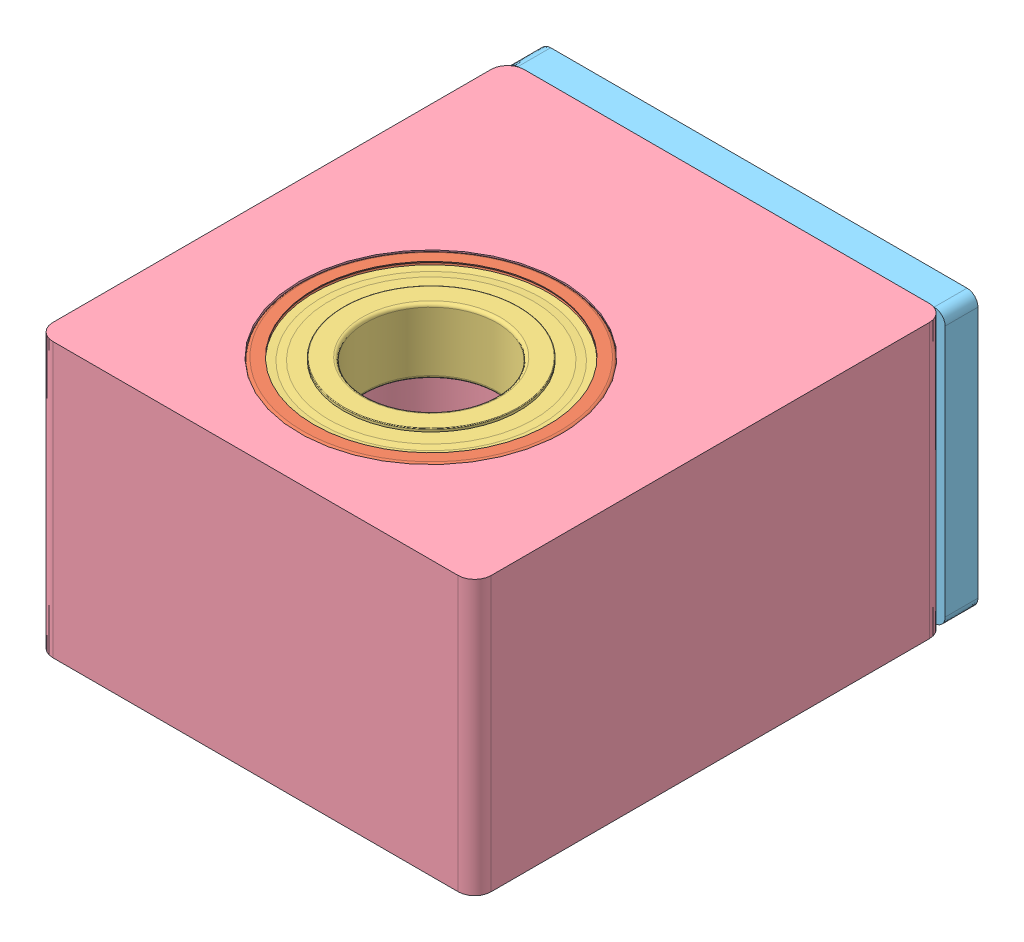
SolidWorks assembly Bearing House v1.step, configuration Default. Lengths in mm.
Overall size (40 25 45.94).
28 component instances, 5 part files, 0 mates.
Components (placement in the parent):
- SKF_61901-2Z.step-1: SKF_61901-2Z.step [Default] at (0 -8 19.5) x (0 -1 0) z (0 0 1) size (6 24 24)
  - SKF_61901-2Z_ball1.step-1: SKF_61901-2Z_ball1.step [Default] at (6 16.2812 -5.2901) x (-1 0 0) z (0 0 1) size (3.18 3.17 3.17)
  - SKF_61901-2Z_ball1.step-2: SKF_61901-2Z_ball1.step [Default] at (6 11.7812 -8.5595) x (-1 0 0) z (0 0 1) size (3.18 3.17 3.17)
  - SKF_61901-2Z_ball1.step-3: SKF_61901-2Z_ball1.step [Default] at (6 6.2188 -8.5595) x (-1 0 0) z (0 0 1) size (3.18 3.17 3.17)
  - SKF_61901-2Z_ball1.step-4: SKF_61901-2Z_ball1.step [Default] at (6 1.7188 -5.2901) x (-1 0 0) z (0 0 1) size (3.18 3.17 3.17)
  - SKF_61901-2Z_ball1.step-5: SKF_61901-2Z_ball1.step [Default] at (6 0 0) x (-1 0 0) z (0 0 1) size (3.18 3.17 3.17)
  - SKF_61901-2Z_ball1.step-6: SKF_61901-2Z_ball1.step [Default] at (6 1.7188 5.2901) x (-1 0 0) z (0 0 1) size (3.18 3.17 3.17)
  - SKF_61901-2Z_ball1.step-7: SKF_61901-2Z_ball1.step [Default] at (6 6.2188 8.5595) x (-1 0 0) z (0 0 1) size (3.18 3.17 3.17)
  - SKF_61901-2Z_ball1.step-8: SKF_61901-2Z_ball1.step [Default] at (6 11.7812 8.5595) x (-1 0 0) z (0 0 1) size (3.18 3.17 3.17)
  - SKF_61901-2Z_ball1.step-9: SKF_61901-2Z_ball1.step [Default] at (6 16.2812 5.2901) x (-1 0 0) z (0 0 1) size (3.18 3.17 3.17)
  - SKF_61901-2Z_ball1.step-10: SKF_61901-2Z_ball1.step [Default] at (6 18 0) x (-1 0 0) z (0 0 1) size (3.18 3.17 3.17)
  - SKF_61901-2Z_or.step-1: SKF_61901-2Z_or.step [Default] x (1 0 0) z (0 0 -1) size (6 24 24)
  - SKF_61901-2Z_ir.step-1: SKF_61901-2Z_ir.step [Default] x (1 0 0) z (0 0 -1) size (6 21.4 21.4)
- SKF_61901-2Z.step-2: SKF_61901-2Z.step [Default] at (0 5 19.5) x (0 1 0) z (0 0 1) size (6 24 24)
  - SKF_61901-2Z_ball1.step-1: SKF_61901-2Z_ball1.step [Default] at (6 16.2812 -5.2901) x (-1 0 0) z (0 0 1) size (3.18 3.17 3.17)
  - SKF_61901-2Z_ball1.step-2: SKF_61901-2Z_ball1.step [Default] at (6 11.7812 -8.5595) x (-1 0 0) z (0 0 1) size (3.18 3.17 3.17)
  - SKF_61901-2Z_ball1.step-3: SKF_61901-2Z_ball1.step [Default] at (6 6.2188 -8.5595) x (-1 0 0) z (0 0 1) size (3.18 3.17 3.17)
  - SKF_61901-2Z_ball1.step-4: SKF_61901-2Z_ball1.step [Default] at (6 1.7188 -5.2901) x (-1 0 0) z (0 0 1) size (3.18 3.17 3.17)
  - SKF_61901-2Z_ball1.step-5: SKF_61901-2Z_ball1.step [Default] at (6 0 0) x (-1 0 0) z (0 0 1) size (3.18 3.17 3.17)
  - SKF_61901-2Z_ball1.step-6: SKF_61901-2Z_ball1.step [Default] at (6 1.7188 5.2901) x (-1 0 0) z (0 0 1) size (3.18 3.17 3.17)
  - SKF_61901-2Z_ball1.step-7: SKF_61901-2Z_ball1.step [Default] at (6 6.2188 8.5595) x (-1 0 0) z (0 0 1) size (3.18 3.17 3.17)
  - SKF_61901-2Z_ball1.step-8: SKF_61901-2Z_ball1.step [Default] at (6 11.7812 8.5595) x (-1 0 0) z (0 0 1) size (3.18 3.17 3.17)
  - SKF_61901-2Z_ball1.step-9: SKF_61901-2Z_ball1.step [Default] at (6 16.2812 5.2901) x (-1 0 0) z (0 0 1) size (3.18 3.17 3.17)
  - SKF_61901-2Z_ball1.step-10: SKF_61901-2Z_ball1.step [Default] at (6 18 0) x (-1 0 0) z (0 0 1) size (3.18 3.17 3.17)
  - SKF_61901-2Z_or.step-1: SKF_61901-2Z_or.step [Default] x (1 0 0) z (0 0 -1) size (6 24 24)
  - SKF_61901-2Z_ir.step-1: SKF_61901-2Z_ir.step [Default] x (1 0 0) z (0 0 -1) size (6 21.4 21.4)
- Universal Bearing Housing.step-1: Universal Bearing Housing.step [Default] at (0 11.0044 14.0358) x (1 0 0) z (0 -1 0) size (40 43 25)
- Universal Bearing Housing Spacer.step-1: Universal Bearing Housing Spacer.step [Default] at (0 -1.5 -7.4) x (1 0 0) z (0 1 0) size (40 3 25)
